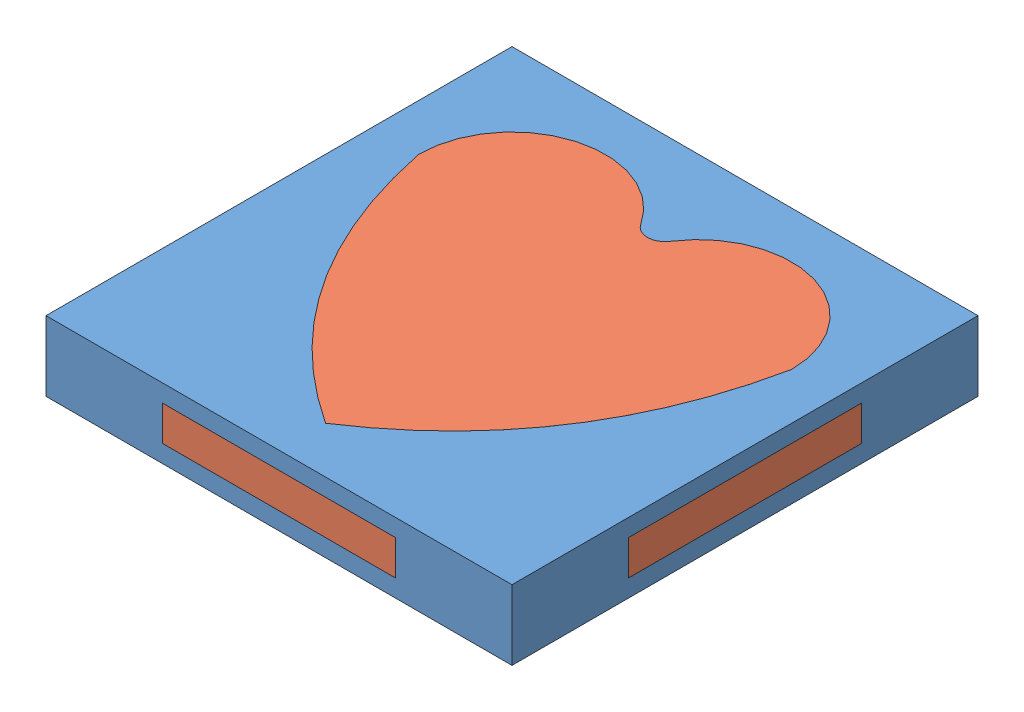
SolidWorks assembly Assem2, configuration Default. Lengths in mm.
Overall size (20 3 20).
2 component instances, 2 part files, 3 mates.
Components (placement in the parent):
- Heart Outer-1: Heart Outer [Default] at (6.3151 10.268 16.0736) size (20 3 20)
- Heart Inner-1: Heart Inner [Default] at (6.3151 10.268 16.0736) size (20 3 20)
Mates (geometry in assembly coordinates):
- Coincident1: coincident: plane of Heart Outer-1 through (16.3151 13.268 26.0736) normal (1 0 0); plane of Heart Inner-1 through (16.3151 12.518 16.0736) normal (1 0 0)
- Coincident2: coincident: plane of Heart Outer-1 through (-3.6849 12.518 21.0736) normal (0 -1 0); plane of Heart Inner-1 through (6.3151 12.518 16.0736) normal (0 1 0)
- Coincident3: coincident anti-aligned: plane of Heart Outer-1 through (-3.6849 12.518 11.0736) normal (0 0 1); plane of Heart Inner-1 through (6.3151 12.518 11.0736) normal (0 0 -1)
